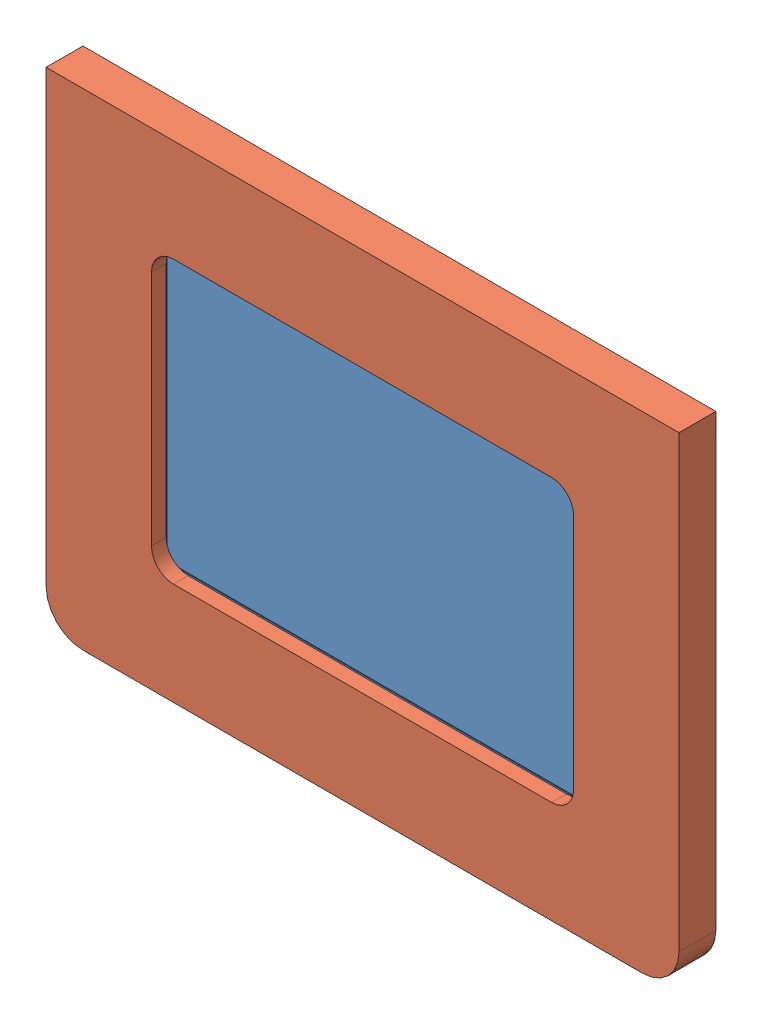
SolidWorks assembly asm-badge_01, configuration Default. Lengths in mm.
Overall size (85.87 66 5).
2 component instances, 2 part files, 3 mates.
Components (placement in the parent):
- prt-epaper-20131111-1: prt-epaper-20131111 [Default] at (-101.3875 8.5091 104.4437) size (74.3 60 2.6)
- prt-case_front-20131111-1: prt-case_front-20131111 [Default] at (-101.3875 8.3091 104.0437) size (85.87 66 5)
Mates (geometry in assembly coordinates):
- Coincident1: coincident aligned: axis of prt-epaper-20131111-1 through (-97.3875 64.3091 104.4437) axis (0 0 1); axis of prt-case_front-20131111-1 through (-97.3875 64.3091 104.0437) axis (0 0 1)
- Coincident2: coincident aligned: axis of prt-epaper-20131111-1 through (-31.0875 64.3091 104.4437) axis (0 0 1); axis of prt-case_front-20131111-1 through (-31.0875 64.3091 104.0437) axis (0 0 1)
- Coincident5: coincident anti-aligned: plane of prt-epaper-20131111-1 through (-101.3875 8.5091 107.0437) normal (0 0 1); plane of prt-case_front-20131111-1 through (-23.5175 10.3091 107.0437) normal (0 0 -1)
